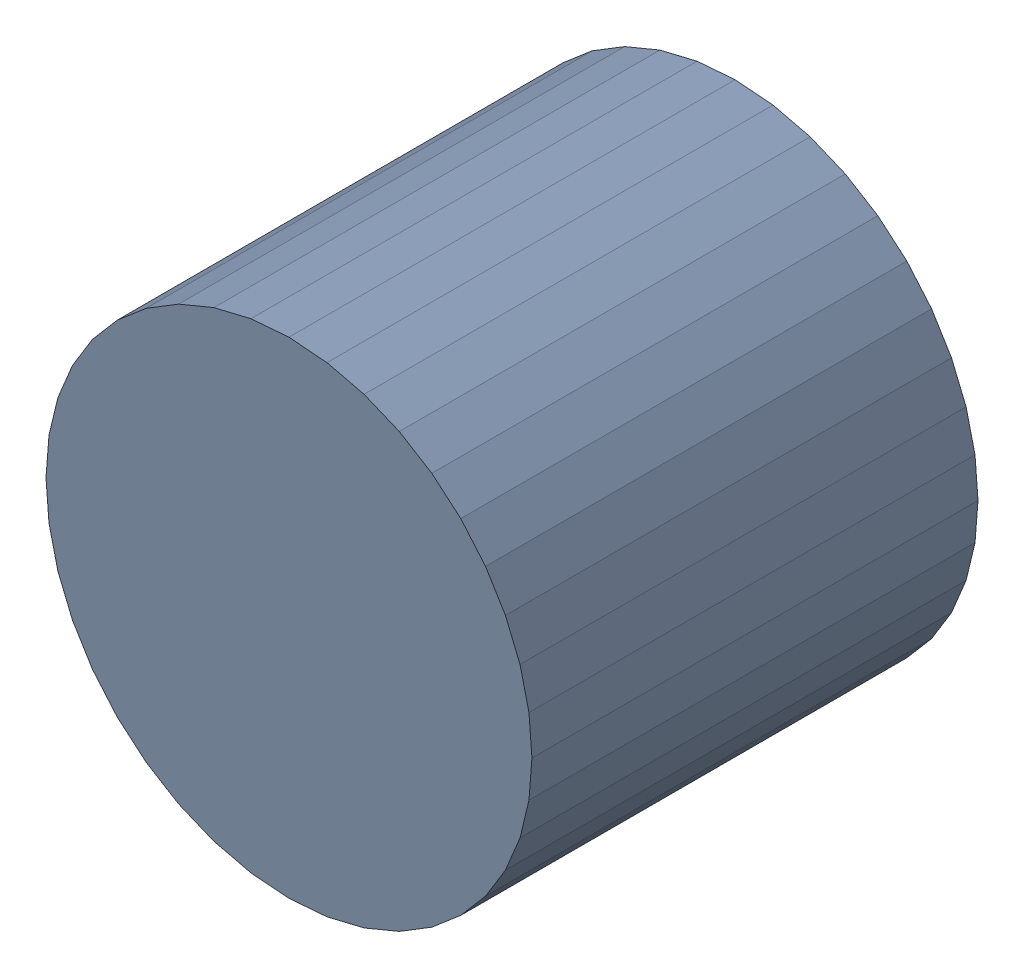
SolidWorks assembly C10_Motor_4Kanaloa_v2.0.0_Motor, configuration Default. Lengths in mm.
Overall size (6.32 6.32 5.8).
2 component instances, 1 part files, 0 mates.
Components (placement in the parent):
- 352892112-1: 352892112 [Default] at (88.959 72.39 0) size (6.32 6.32 5.8)
  - Extruded_11-1: Extruded_11 [Default] at origin size (6.32 6.32 5.8)
